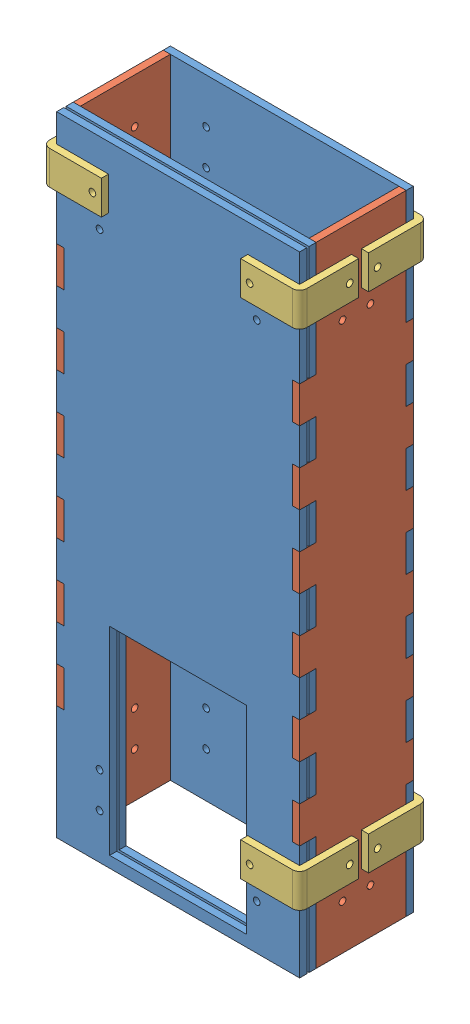
SolidWorks assembly Interaction_Box, configuration Default. Lengths in mm.
Overall size (114.3 279.4 56.88).
12 component instances, 3 part files, 28 mates.
Components (placement in the parent):
- front_back-1: front_back [Front] at (114.8789 48.9442 274.6837) size (107.95 279.4 3.17)
- side-1: side [Side] at (114.8789 48.9442 230.5087) x (0 0 1) z (-1 0 0) size (50.52 279.4 3.17)
- side-2: side [Side] at (216.4789 328.3442 230.5087) x (0 0 1) z (1 0 0) size (50.52 279.4 3.17)
- front_back-2: front_back [Side] at (114.8789 48.9442 227.3337) size (107.95 279.4 3.17)
- front_back-3: front_back [Front] at (114.8789 48.9442 270.5087) size (107.95 279.4 3.17)
- wall_bracket-5: wall_bracket [half_size] at (111.7039 315.8442 227.3337) x (0 -1 0) z (-1 0 0) size (15 26.23 26.23)
- wall_bracket-6: wall_bracket [half_size] at (111.7039 315.8442 277.8587) x (0 -1 0) z (0 0 1) size (15 26.23 26.23)
- wall_bracket-7: wall_bracket [half_size] at (219.6539 300.8442 277.8587) x (0 1 0) z (0 0 1) size (15 26.23 26.23)
- wall_bracket-8: wall_bracket [half_size] at (111.7039 77.1942 227.3337) x (0 1 0) z (0 0 -1) size (15 26.23 26.23)
- wall_bracket-9: wall_bracket [half_size] at (219.6539 92.1942 277.8587) x (0 -1 0) z (1 0 0) size (15 26.23 26.23)
- wall_bracket-10: wall_bracket [half_size] at (219.6539 300.8442 227.3337) x (0 1 0) z (1 0 0) size (15 26.23 26.23)
- wall_bracket-11: wall_bracket [half_size] at (219.6539 77.1942 227.3337) x (0 1 0) z (1 0 0) size (15 26.23 26.23)
Mates (geometry in assembly coordinates):
- Coincident10: coincident anti-aligned: plane of side-1 through (111.7039 48.9442 270.5087) normal (0 0 1); plane of front_back-3 through (114.8789 48.9442 270.5087) normal (0 0 -1)
- Coincident11: coincident anti-aligned: plane of front_back-1 through (114.8789 48.9442 277.8587) normal (0 0 1); plane of wall_bracket-6 through (111.7039 300.8442 277.8587) normal (0 0 -1)
- Concentric1: concentric aligned: cylinder of front_back-1 through (130.7539 308.3442 270.4411) axis (0 0 1) radius 1.5; cylinder of wall_bracket-6 through (130.7539 308.3442 273.6161) axis (0 0 1) radius 1.5
- Concentric2: concentric aligned: cylinder of side-1 through (119.1215 308.3442 258.8087) axis (-1 0 0) radius 1.5; cylinder of wall_bracket-6 through (115.9465 308.3442 258.8087) axis (-1 0 0) radius 1.5
- Coincident12: coincident anti-aligned: plane of front_back-2 through (114.8789 48.9442 227.3337) normal (0 0 -1); plane of wall_bracket-8 through (111.7039 92.1942 227.3337) normal (0 0 1)
- Concentric3: concentric anti-aligned: cylinder of front_back-2 through (130.7539 84.6942 223.0911) axis (0 0 1) radius 1.5; cylinder of wall_bracket-8 through (130.7539 84.6942 231.5764) axis (0 0 -1) radius 1.5
- Coincident13: coincident anti-aligned: plane of side-1 through (111.7039 48.9442 230.5087) normal (-1 0 0); plane of wall_bracket-8 through (111.7039 92.1942 250.3837) normal (1 0 0)
- Coincident14: coincident anti-aligned: plane of front_back-2 through (114.8789 48.9442 227.3337) normal (0 0 -1); plane of wall_bracket-5 through (134.7539 300.8442 227.3337) normal (0 0 1)
- Concentric5: concentric anti-aligned: cylinder of front_back-2 through (130.7539 308.3442 223.0911) axis (0 0 1) radius 1.5; cylinder of wall_bracket-5 through (130.7539 308.3442 231.5764) axis (0 0 -1) radius 1.5
- Coincident15: coincident anti-aligned: plane of side-1 through (111.7039 48.9442 230.5087) normal (-1 0 0); plane of wall_bracket-5 through (111.7039 300.8442 227.3337) normal (1 0 0)
- Concentric6: concentric aligned: cylinder of side-1 through (119.1215 84.6942 246.3837) axis (-1 0 0) radius 1.5; cylinder of wall_bracket-8 through (115.9465 84.6942 246.3837) axis (-1 0 0) radius 1.5
- Concentric7: concentric aligned: cylinder of side-1 through (119.1215 308.3442 246.3837) axis (-1 0 0) radius 1.5; cylinder of wall_bracket-5 through (115.9465 308.3442 246.3837) axis (-1 0 0) radius 1.5
- Coincident16: coincident anti-aligned: plane of front_back-1 through (114.8789 48.9442 277.8587) normal (0 0 1); plane of wall_bracket-7 through (219.6539 315.8442 277.8587) normal (0 0 -1)
- Concentric8: concentric aligned: cylinder of front_back-1 through (200.6039 308.3442 270.4411) axis (0 0 1) radius 1.5; cylinder of wall_bracket-7 through (200.6039 308.3442 273.6161) axis (0 0 1) radius 1.5
- Coincident17: coincident anti-aligned: plane of side-2 through (219.6539 328.3442 230.5087) normal (1 0 0); plane of wall_bracket-7 through (219.6539 315.8442 254.8087) normal (-1 0 0)
- Concentric9: concentric aligned: cylinder of wall_bracket-7 through (215.4112 308.3442 258.8087) axis (1 0 0) radius 1.5; cylinder of side-2 through (212.2362 308.3442 258.8087) axis (1 0 0) radius 1.5
- Coincident18: coincident anti-aligned: plane of front_back-1 through (114.8789 48.9442 277.8587) normal (0 0 1); plane of wall_bracket-9 through (196.6039 77.1942 277.8587) normal (0 0 -1)
- Concentric10: concentric aligned: cylinder of front_back-1 through (200.6039 84.6942 270.4411) axis (0 0 1) radius 1.5; cylinder of wall_bracket-9 through (200.6039 84.6942 273.6161) axis (0 0 1) radius 1.5
- Concentric13: concentric aligned: circle of side-2; cylinder of wall_bracket-9 through (215.4112 84.6942 258.8087) axis (1 0 0) radius 1.5
- Coincident21: coincident anti-aligned: plane of side-1 through (111.7039 48.9442 230.5087) normal (-1 0 0); plane of wall_bracket-6 through (111.7039 300.8442 254.8087) normal (1 0 0)
- Coincident22: coincident anti-aligned: plane of front_back-2 through (114.8789 48.9442 227.3337) normal (0 0 -1); plane of wall_bracket-10 through (196.6039 315.8442 227.3337) normal (0 0 1)
- Concentric14: concentric anti-aligned: cylinder of front_back-2 through (200.6039 308.3442 223.0911) axis (0 0 1) radius 1.5; cylinder of wall_bracket-10 through (200.6039 308.3442 231.5764) axis (0 0 -1) radius 1.5
- Concentric15: concentric aligned: cylinder of side-2 through (212.2362 308.3442 246.3837) axis (1 0 0) radius 1.5; cylinder of wall_bracket-10 through (215.4112 308.3442 246.3837) axis (1 0 0) radius 1.5
- Coincident23: coincident anti-aligned: plane of front_back-2 through (114.8789 48.9442 227.3337) normal (0 0 -1); plane of wall_bracket-11 through (196.6039 92.1942 227.3337) normal (0 0 1)
- Concentric16: concentric anti-aligned: cylinder of front_back-2 through (200.6039 84.6942 223.0911) axis (0 0 1) radius 1.5; cylinder of wall_bracket-11 through (200.6039 84.6942 231.5764) axis (0 0 -1) radius 1.5
- Concentric17: concentric aligned: cylinder of side-2 through (212.2362 84.6942 246.3837) axis (1 0 0) radius 1.5; cylinder of wall_bracket-11 through (215.4112 84.6942 246.3837) axis (1 0 0) radius 1.5
- Concentric19: concentric aligned: cylinder of front_back-3 through (130.7539 308.3442 266.2661) axis (0 0 1) radius 1.5; cylinder of wall_bracket-6 through (130.7539 308.3442 273.6161) axis (0 0 1) radius 1.5
- Concentric20: concentric aligned: cylinder of front_back-3 through (200.6039 308.3442 266.2661) axis (0 0 1) radius 1.5; cylinder of wall_bracket-7 through (200.6039 308.3442 273.6161) axis (0 0 1) radius 1.5
